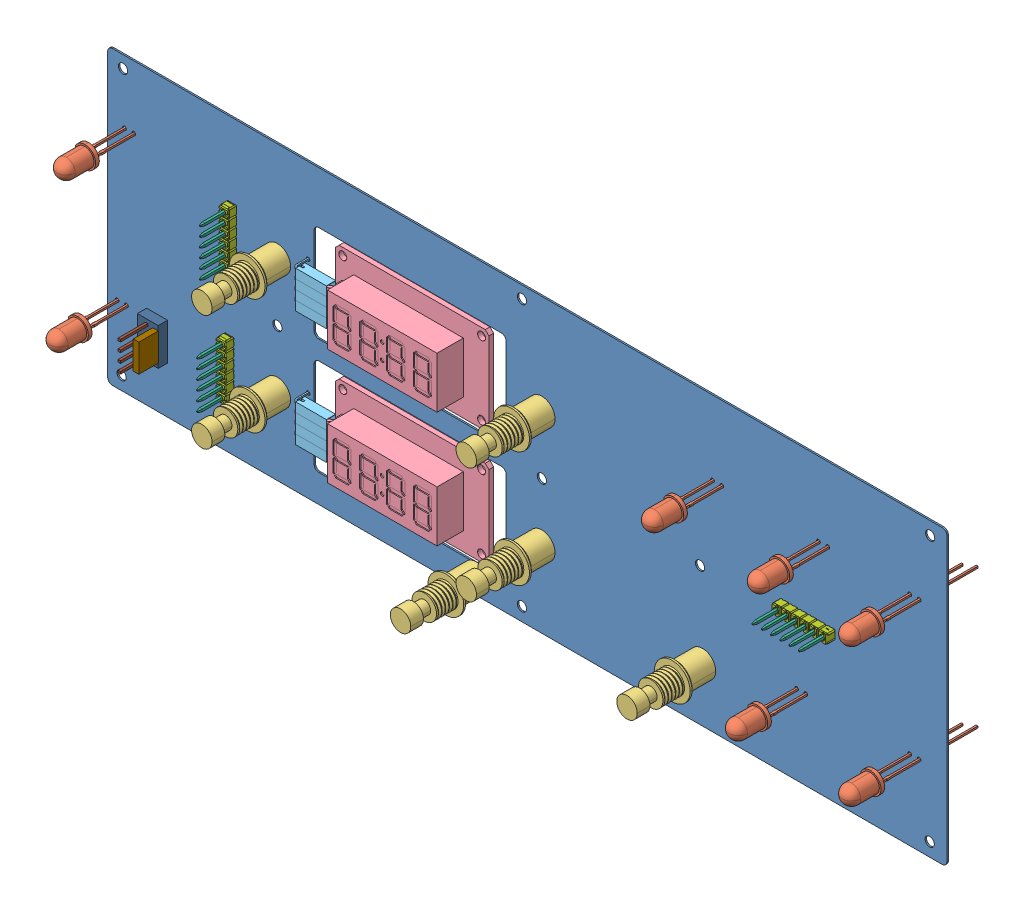
SolidWorks assembly Final Second_PCB.step, configuration Default. Lengths in mm.
Overall size (229.74 80.43 36.54).
74 component instances, 11 part files, 0 mates.
Components (placement in the parent):
- Board.step-1: Board.step [Default] at origin size (229.74 79.88 0.41)
  - Open CASCADE STEP translator 7.5 4.1.1.step-1: Open CASCADE STEP translator 7.5 4.1.1.step [Default] at (0 0 -0.4115) size (229.74 79.88 0.41)
- Error LED.step-1: Error LED.step [Default] at origin size (5.45 5.9 35.6)
  - WP7113SEC_J3.step-1: WP7113SEC_J3.step [Default] at (6.0371 62.672 10.16) x (1 0 0) z (0 -1 0) size (5.45 35.6 5.9)
    - WP7113ID_WP7113ID.step-1: WP7113ID_WP7113ID.step [Default] at (0 1 0) size (5.45 35.6 5.9)
- Power LED.step-1: Power LED.step [Default] at origin size (5.45 5.9 35.6)
  - WP7113SEC_J3.step-1: WP7113SEC_J3.step [Default] at (4.0371 20.912 10.16) x (1 0 0) z (0 -1 0) size (5.45 35.6 5.9)
    - WP7113ID_WP7113ID.step-1: WP7113ID_WP7113ID.step [Default] at (0 1 0) size (5.45 35.6 5.9)
- MODE 3.step-1: MODE 3.step [Default] at origin size (5.45 5.9 35.6)
  - WP7113SEC_J3.step-1: WP7113SEC_J3.step [Default] at (221.0371 59.672 10.16) x (1 0 0) z (0 -1 0) size (5.45 35.6 5.9)
    - WP7113ID_WP7113ID.step-1: WP7113ID_WP7113ID.step [Default] at (0 1 0) size (5.45 35.6 5.9)
- MODE 4.step-1: MODE 4.step [Default] at origin size (5.45 5.9 35.6)
  - WP7113SEC_J3.step-1: WP7113SEC_J3.step [Default] at (190.0371 21.772 10.16) x (1 0 0) z (0 -1 0) size (5.45 35.6 5.9)
    - WP7113ID_WP7113ID.step-1: WP7113ID_WP7113ID.step [Default] at (0 1 0) size (5.45 35.6 5.9)
- MODE 2.step-1: MODE 2.step [Default] at origin size (5.45 5.9 35.6)
  - WP7113SEC_J3.step-1: WP7113SEC_J3.step [Default] at (196.0371 59.672 10.16) x (1 0 0) z (0 -1 0) size (5.45 35.6 5.9)
    - WP7113ID_WP7113ID.step-1: WP7113ID_WP7113ID.step [Default] at (0 1 0) size (5.45 35.6 5.9)
- MODE Changer.step-1: MODE Changer.step [Default] at origin size (9.8 9.8 27.2)
  - yellow Push buton.step-1: yellow Push buton.step [Default] at (163 14.943 0) size (9.8 9.8 27.2)
- Timer +.step-1: Timer +.step [Default] at origin size (9.8 9.8 27.2)
  - yellow Push buton.step-1: yellow Push buton.step [Default] at (119 21.043 0) size (9.8 9.8 27.2)
- Temp +.step-1: Temp +.step [Default] at origin size (9.8 9.8 27.2)
  - yellow Push buton.step-1: yellow Push buton.step [Default] at (119 52.743 0) size (9.8 9.8 27.2)
- Timer -.step-1: Timer -.step [Default] at origin size (9.8 9.8 27.2)
  - yellow Push buton.step-1: yellow Push buton.step [Default] at (46.6 21.043 0) size (9.8 9.8 27.2)
- Temp -.step-1: Temp -.step [Default] at origin size (9.8 9.8 27.2)
  - yellow Push buton.step-1: yellow Push buton.step [Default] at (46.6 52.743 0) x (1 0 0) z (0 0 1) size (9.8 9.8 27.2)
- Timer off.step-1: Timer off.step [Default] at origin size (9.8 9.8 27.2)
  - yellow Push buton.step-1: yellow Push buton.step [Default] at (101 4.483 0) size (9.8 9.8 27.2)
- Timer Display.step-1: Timer Display.step [Default] at origin size (50.11 24 11)
  - Display.step-1: Display.step [Default] at (67.4531 24.905 -6.858) x (-1 0 0) z (0 0 1) size (50.11 24 11)
    - Display TM1637.step.step-1: Display TM1637.step.step [Default] at (-16.3981 3.862 5.9151) size (47.4 24 11)
    - Female90deg_4pin.STEP.step-1: Female90deg_4pin.STEP.step [Default] at (10.7558 1.042 11.9551) x (-1 0 0) z (0 -1 0) size (10.35 6.14 10.16)
- Temp Display.step-1: Temp Display.step [Default] at origin size (50.11 24 11)
  - Display.step-1: Display.step [Default] at (67.4531 56.605 -6.858) x (-1 0 0) z (0 0 1) size (50.11 24 11)
    - Display TM1637.step.step-1: Display TM1637.step.step [Default] at (-16.3981 3.862 5.9151) size (47.4 24 11)
    - Female90deg_4pin.STEP.step-1: Female90deg_4pin.STEP.step [Default] at (10.7558 1.042 11.9551) x (-1 0 0) z (0 -1 0) size (10.35 6.14 10.16)
- MODE 1.step-1: MODE 1.step [Default] at origin size (5.45 5.9 35.6)
  - WP7113SEC_J3.step-1: WP7113SEC_J3.step [Default] at (167.0371 59.672 10.16) x (1 0 0) z (0 -1 0) size (5.45 35.6 5.9)
    - WP7113ID_WP7113ID.step-1: WP7113ID_WP7113ID.step [Default] at (0 1 0) size (5.45 35.6 5.9)
- MODE 5.step-1: MODE 5.step [Default] at origin size (5.45 5.9 35.6)
  - WP7113SEC_J3.step-1: WP7113SEC_J3.step [Default] at (221.0371 21.772 10.16) x (1 0 0) z (0 -1 0) size (5.45 35.6 5.9)
    - WP7113ID_WP7113ID.step-1: WP7113ID_WP7113ID.step [Default] at (0 1 0) size (5.45 35.6 5.9)
- Timer.step-1: Timer.step [Default] at origin size (2.49 15.24 12.06)
  - Conn_Molex_22-28-4060_eec.step-1: Conn_Molex_22-28-4060_eec.step [Default] at (33.528 20.701 0) x (0 1 0) z (0 0 1) size (15.24 2.49 12.06)
    - 1.step-1: 1.step [Default] at (0 -0.0001 1.143) x (1 0 0) z (0 -1 0) size (15.24 12.06 2.49)
      - 1-0.step-1: 1-0.step [Default] at origin size (13.36 12.06 0.66)
      - 022284060.step-1: 022284060.step [Default] at origin size (15.24 2.54 2.49)
    - Molex Logo.step-1: Molex Logo.step [Default] at (-6.6696 -1.1457 0.894) x (1 0 0) z (0 -1 0) size (1.14 0.28 0.1)
- Temperature.step-1: Temperature.step [Default] at origin size (2.49 15.24 12.06)
  - Conn_Molex_22-28-4060_eec.step-1: Conn_Molex_22-28-4060_eec.step [Default] at (34.29 52.451 0) x (0 1 0) z (0 0 1) size (15.24 2.49 12.06)
    - 1.step-1: 1.step [Default] at (0 -0.0001 1.143) x (1 0 0) z (0 -1 0) size (15.24 12.06 2.49)
      - 1-0.step-1: 1-0.step [Default] at origin size (13.36 12.06 0.66)
      - 022284060.step-1: 022284060.step [Default] at origin size (15.24 2.54 2.49)
    - Molex Logo.step-1: Molex Logo.step [Default] at (-6.6696 -1.1457 0.894) x (1 0 0) z (0 -1 0) size (1.14 0.28 0.1)
- Power, Error & Timer off.step-1: Power, Error & Timer off.step [Default] at origin size (5.72 10.16 13.59)
  - 6305125328.step-1: 6305125328.step [Default] at (15.7505 18.034 2.54) size (1.53 7.62 5.33)
    - Extruded.step-1: Extruded.step [Default] at origin size (1.53 7.62 5.33)
  - 6305117888.step-1: 6305117888.step [Default] at (13.6525 18.034 0) size (5.71 10.16 2.54)
    - Extruded-1.step-1: Extruded-1.step [Default] at origin size (5.71 10.16 2.54)
  - 6305122208.step-1: 6305122208.step [Default] at (13.3351 21.8439 -3.56) size (0.64 0.64 13.59)
    - Extruded-2.step-1: Extruded-2.step [Default] at origin size (0.64 0.64 13.59)
  - 6305122208.step-2: 6305122208.step [Default] at (13.3352 14.2239 -3.56) size (0.64 0.64 13.59)
    - Extruded-2.step-1: Extruded-2.step [Default] at origin size (0.64 0.64 13.59)
  - 6305122208.step-3: 6305122208.step [Default] at (13.335 16.7639 -3.56) size (0.64 0.64 13.59)
    - Extruded-2.step-1: Extruded-2.step [Default] at origin size (0.64 0.64 13.59)
  - 6305122208.step-4: 6305122208.step [Default] at (13.3351 19.3039 -3.56) size (0.64 0.64 13.59)
    - Extruded-2.step-1: Extruded-2.step [Default] at origin size (0.64 0.64 13.59)
- Mode LED , Changer.step-1: Mode LED , Changer.step [Default] at origin size (15.24 2.49 12.06)
  - Conn_Molex_22-28-4060_eec.step-1: Conn_Molex_22-28-4060_eec.step [Default] at (191.897 40.005 0) x (-1 0 0) z (0 0 1) size (15.24 2.49 12.06)
    - 1.step-1: 1.step [Default] at (0 -0.0001 1.143) x (1 0 0) z (0 -1 0) size (15.24 12.06 2.49)
      - 1-0.step-1: 1-0.step [Default] at origin size (13.36 12.06 0.66)
      - 022284060.step-1: 022284060.step [Default] at origin size (15.24 2.54 2.49)
    - Molex Logo.step-1: Molex Logo.step [Default] at (-6.6696 -1.1457 0.894) x (1 0 0) z (0 -1 0) size (1.14 0.28 0.1)
